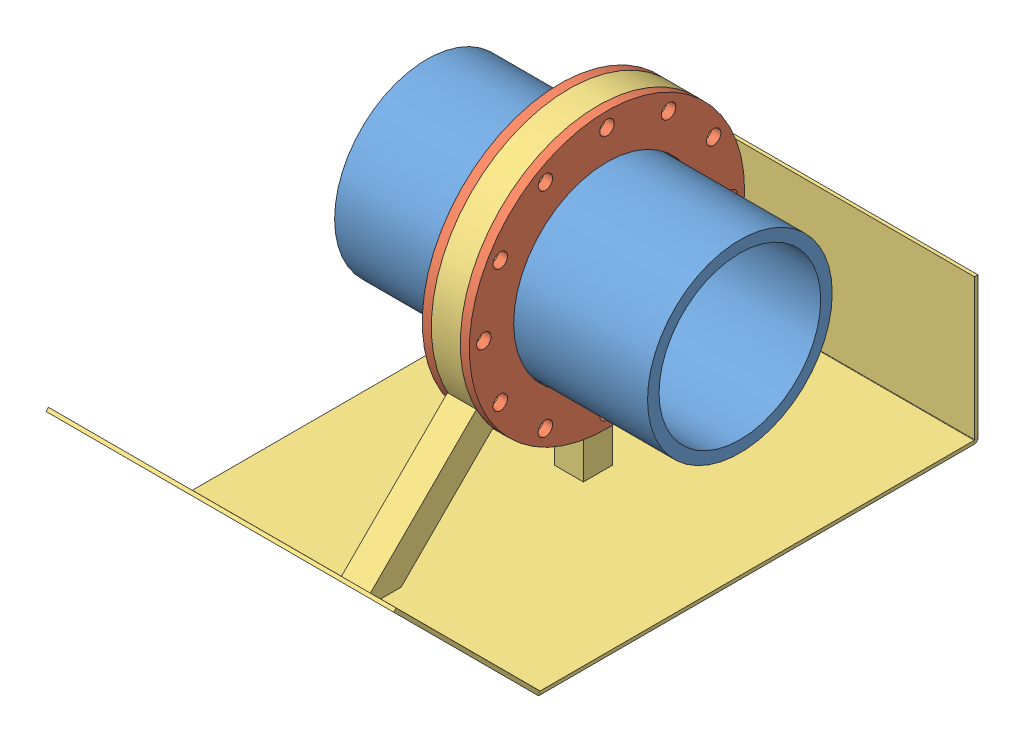
SolidWorks assembly Bracket FC Assembly, configuration Default. Lengths in mm.
Overall size (609.6 564.8 1024.45).
5 component instances, 3 part files, 5 mates.
Components (placement in the parent):
- 12_NOM_Flange_Adapter-1: 12_NOM_Flange_Adapter [Default] at origin size (274.32 381 381)
- Class_150_Slip-On_Plate_Flange-1: Class_150_Slip-On_Plate_Flange [Default] at (41.275 0 0) x (0 0 1) z (-1 0 0) size (482.6 482.6 15.88)
- 12_NOM_Flange_Adapter-3: 12_NOM_Flange_Adapter [Default] x (-1 0 0) z (0 0 -1) size (274.32 381 381)
- Class_150_Slip-On_Plate_Flange-2: Class_150_Slip-On_Plate_Flange [Default] at (-41.275 0 0) x (0 0 1) z (1 0 0) size (482.6 482.6 15.88)
- Bracket FC-1: Bracket FC [Default<As Machined>] at (25.4 0 0) x (0 0 1) z (-1 0 0) size (1024.45 564.8 609.6)
Mates (geometry in assembly coordinates):
- Concentric1: concentric anti-aligned: cylinder of 12_NOM_Flange_Adapter-1 through (0 0 0) axis (-1 0 0) radius 161.925; cylinder of Class_150_Slip-On_Plate_Flange-1 through (25.4 0 0) axis (1 0 0) radius 163.576
- Coincident1: coincident anti-aligned: plane of 12_NOM_Flange_Adapter-1 through (25.4 161.925 0) normal (1 0 0); plane of Class_150_Slip-On_Plate_Flange-1 through (25.4 0 0) normal (-1 0 0)
- Coincident4: coordinate: point of 12_NOM_Flange_Adapter-1
- Concentric2: concentric anti-aligned: cylinder of 12_NOM_Flange_Adapter-1 through (0 0 0) axis (-1 0 0) radius 190.5; cylinder of Bracket FC-1 through (-25.4 0 0) axis (1 0 0) radius 190.5
- Coincident5: coincident anti-aligned: plane of Class_150_Slip-On_Plate_Flange-1 through (25.4 0 0) normal (-1 0 0); plane of Bracket FC-1 through (25.4 0 0) normal (1 0 0)
